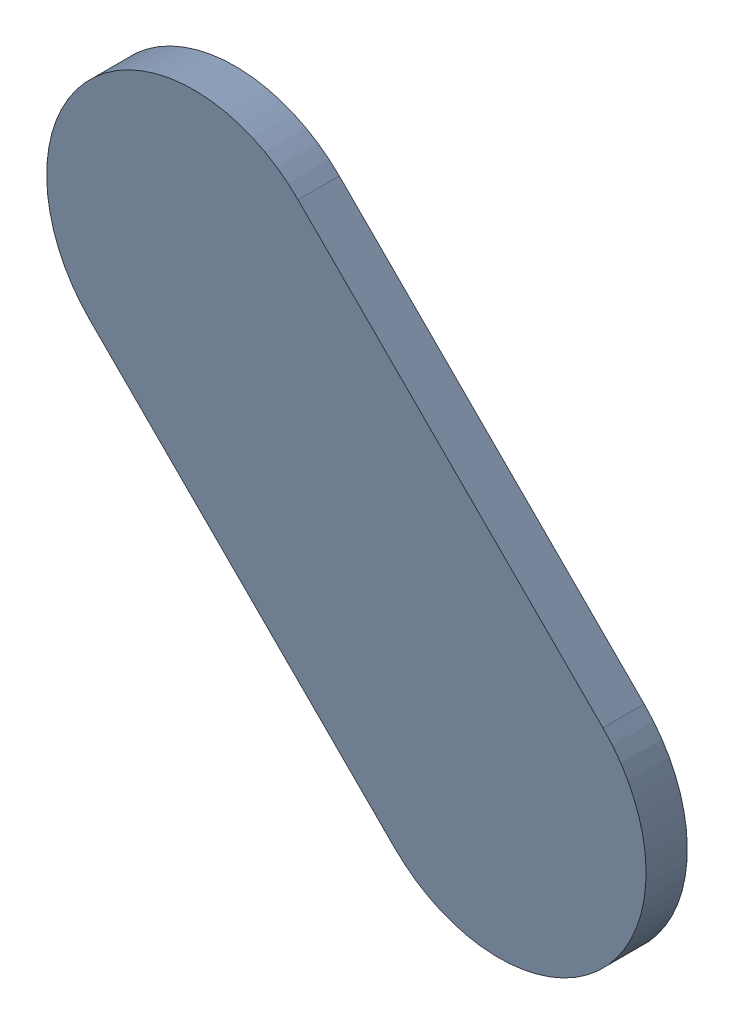
SolidWorks assembly Track (27.537mm,43.763mm)(27.8mm,43.5mm) on Top Layer, configuration Predeterminado. Lengths in mm.
Overall size (0.52 0.52 0.04).
2 component instances, 1 part files, 0 mates.
Components (placement in the parent):
- Track (27.537mm,43.763mm)(27.8mm,43.5mm) on Top Layer-1-1: Track (27.537mm,43.763mm)(27.8mm,43.5mm) on Top Layer-1 [Predeterminado] at (-68.317 -44.187 -0.0457) size (0.52 0.52 0.04)
  - Track (27.537mm,43.763mm)(27.8mm,43.5mm) on Top Layer-Part-1-1: Track (27.537mm,43.763mm)(27.8mm,43.5mm) on Top Layer-Part-1 [Predeterminado] at origin size (0.52 0.52 0.04)
